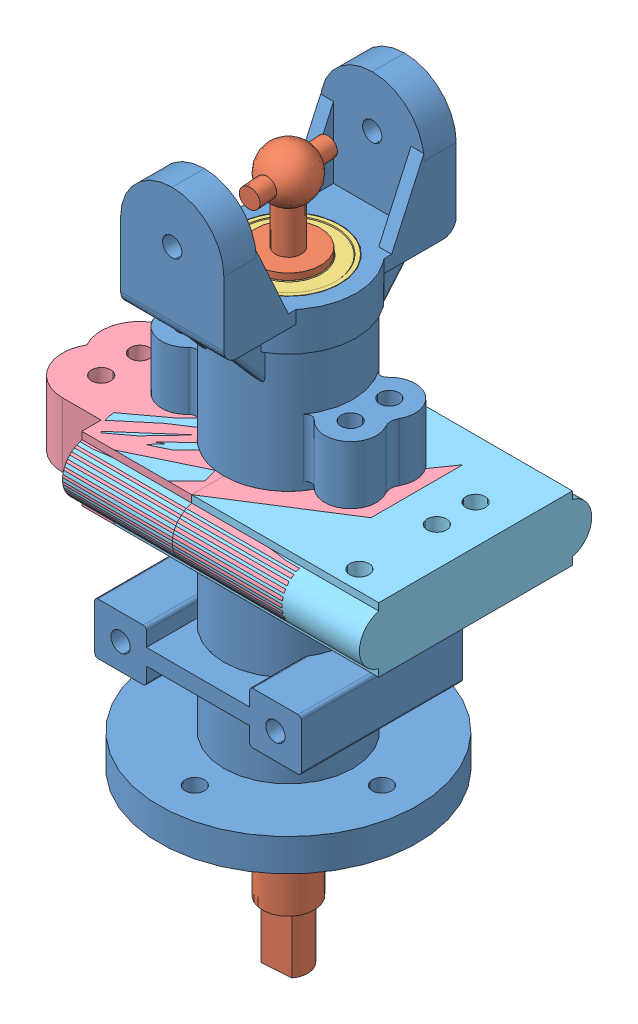
SolidWorks assembly Short_axle, configuration Default. Lengths in mm.
Overall size (58 113 72).
6 component instances, 5 part files, 13 mates.
Components (placement in the parent):
- Short_axle-1: Short_axle [Default] at origin size (40 89 40)
- Short_shaft-1: Short_shaft [Default] at (0 86 0) x (-0.074261 0 -0.997239) z (0 1 0) size (13 10 110)
- 688zz-1: 688zz [Default] x (0.294496 0 -0.955653) z (0.955653 0 0.294496) size (16 5 16)
- 688zz-2: 688zz [Default] at (0 66 0) x (0.717038 0 -0.697034) z (0.697034 0 0.717038) size (16 5 16)
- Spring_coupler-1: Spring_coupler [Default] at (0 36.25 0) x (0 0 -1) z (0 1 0) size (36 46 10)
- Spring_coupler_mod-1: Spring_coupler_mod [Default] at (0 36.25 0) x (0 0 1) z (0 1 0) size (70 46 10)
Mates (geometry in assembly coordinates):
- Coincident1: coordinate: point of Short_axle-1; point of assembly
- Concentric1: concentric aligned: cylinder of Short_axle-1 through (0 0 0) axis (0 1 0) radius 4.5; cylinder of Short_shaft-1 through (0 86 0) axis (0 1 0) radius 2
- Coincident2: coincident anti-aligned: plane of Short_axle-1 through (0 71 0) normal (0 1 0); plane of Short_shaft-1 through (-4.9862 71 0.3713) normal (0 -1 0)
- Concentric2: concentric anti-aligned: cylinder of Short_axle-1 through (0 5 0) axis (0 -1 0) radius 8; cylinder of 688zz-1 through (0 0 0) axis (0 1 0) radius 8
- Coincident3: coincident aligned: plane of Short_axle-1 through (0 0 0) normal (0 -1 0); plane of 688zz-1 through (0 0 0) normal (0 -1 0)
- Coincident4: coincident aligned: plane of Short_axle-1 through (0 71 0) normal (0 1 0); plane of 688zz-2 through (0 71 0) normal (0 1 0)
- Concentric3: concentric aligned: cylinder of Short_axle-1 through (0 66 0) axis (0 1 0) radius 8; cylinder of 688zz-2 through (0 66 0) axis (0 1 0) radius 8
- Concentric4: concentric aligned: cylinder of Short_axle-1 through (0 71 0) axis (0 -1 0) radius 10; cylinder of Spring_coupler-1 through (0 46.25 0) axis (0 -1 0) radius 10
- Coincident5: coincident anti-aligned: plane of Short_axle-1 through (11 0 0) normal (1 0 0); plane of Spring_coupler-1 through (11 36.25 0) normal (-1 0 0)
- Coincident6: coincident anti-aligned: plane of Short_axle-1 through (11 40 10) normal (0 -1 0); plane of Spring_coupler-1 through (0 40 0) normal (0 1 0)
- Concentric5: concentric: cylinder of Short_axle-1 through (0 71 0) axis (0 -1 0) radius 10; cylinder of Spring_coupler_mod-1 through (0 46.25 0) axis (0 -1 0) radius 10
- Coincident7: coincident: plane of Short_axle-1 through (11 0 0) normal (1 0 0); plane of Spring_coupler_mod-1 through (11 36.25 0) normal (-1 0 0)
- Coincident8: coincident anti-aligned: plane of Short_axle-1 through (11 42.5 10) normal (0 1 0); plane of Spring_coupler_mod-1 through (0 42.5 0) normal (0 -1 0)
